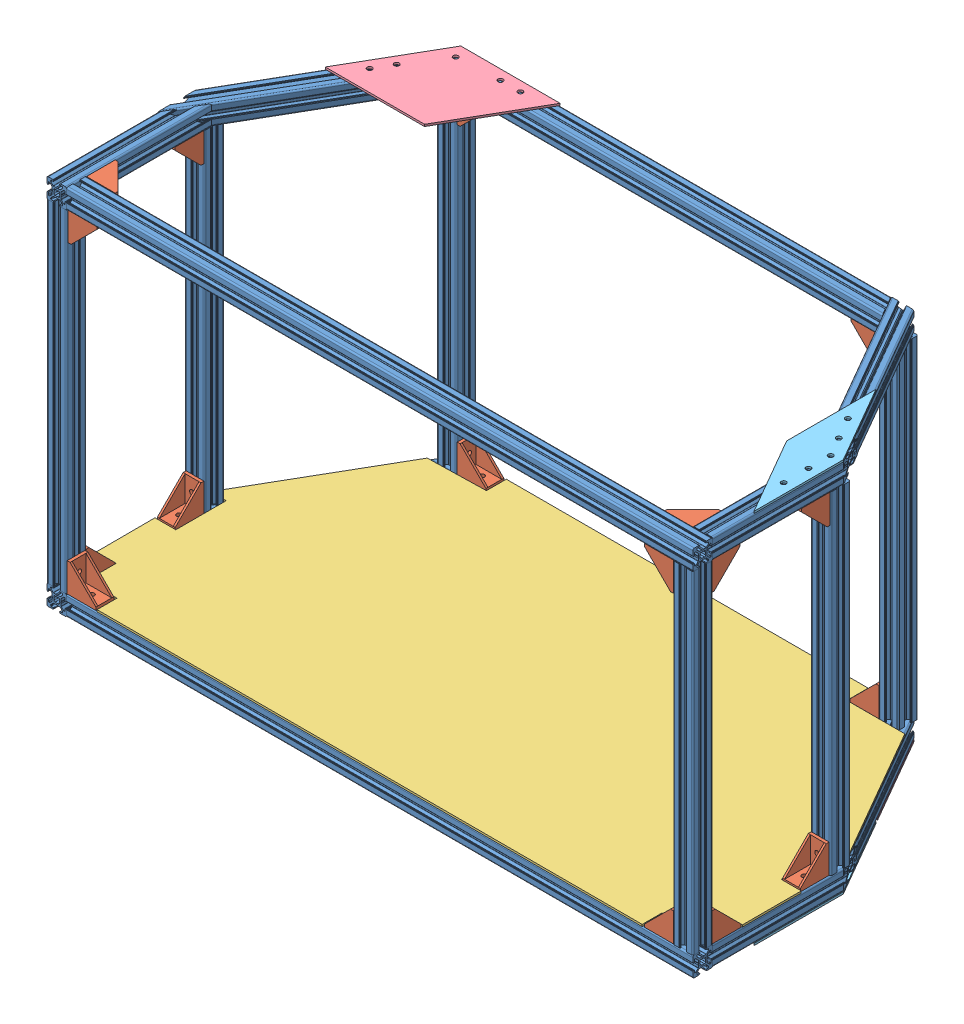
SolidWorks assembly RC, configuration Default. Lengths in mm.
Overall size (773.94 377 335.26).
30 component instances, 5 part files, 86 mates.
Components (placement in the parent):
- Rear Compartment Chassis-1: Rear Compartment Chassis [Default<As Machined>] at (565.8502 119.352 674.9495) x (0 -1 0) z (-1 0 0) size (375 320 651)
- L- Bracket-1: L- Bracket [Default] at (-55.1513 119.8531 664.9511) x (0 -1 0) z (0 0 1) size (18 29 29)
- L- Bracket-2: L- Bracket [Default] at (-55.1513 129.3509 675.4511) x (0 0 1) z (-1 0 0) size (18 29 29)
- L- Bracket-3: L- Bracket [Default] at (-64.65 129.3509 664.9506) size (18 29 29)
- L- Bracket-4: L- Bracket [Default] at (37.8598 464.3531 375.4493) x (0 0 1) z (0 1 0) size (18 29 29)
- L- Bracket-5: L- Bracket [Default] at (462.8389 464.3531 374.448) x (0 0 -1) z (0 1 0) size (18 29 29)
- L- Bracket-6: L- Bracket [Default] at (565.3487 129.3509 546.0484) x (-1 0 0) z (0 0 -1) size (18 29 29)
- L- Bracket-7: L- Bracket [Default] at (462.8389 129.3509 375.4493) x (0 0 1) z (0 -1 0) size (18 29 29)
- L- Bracket-8: L- Bracket [Default] at (565.3487 464.3531 664.9506) x (-1 0 0) z (0 0 1) size (18 29 29)
- L- Bracket-9: L- Bracket [Default] at (555.8517 119.8531 664.9511) x (0 -1 0) z (1 0 0) size (18 29 29)
- L- Bracket-10: L- Bracket [Default] at (555.85 129.3509 675.4511) x (0 0 1) z (0 -1 0) size (18 29 29)
- L- Bracket-12: L- Bracket [Default] at (566.35 129.3509 664.9506) size (18 29 29)
- L- Bracket-14: L- Bracket [Default] at (555.8517 473.8509 664.9511) x (0 1 0) z (0 0 1) size (18 29 29)
- L- Bracket-15: L- Bracket [Default] at (-55.1513 464.3531 674.4484) x (0 0 1) z (0 1 0) size (18 29 29)
- L- Bracket-17: L- Bracket [Default] at (-55.1513 474.8531 664.9511) x (0 -1 0) z (0 0 1) size (18 29 29)
- L- Bracket-19: L- Bracket [Default] at (555.85 464.3531 675.4506) x (0 0 -1) z (0 1 0) size (18 29 29)
- L- Bracket-20: L- Bracket [Default] at (566.35 464.3531 546.0484) x (-1 0 0) z (0 1 0) size (18 29 29)
- L- Bracket-21: L- Bracket [Default] at (-65.6513 464.3531 664.9506) x (1 0 0) z (0 1 0) size (18 29 29)
- L- Bracket-22: L- Bracket [Default] at (37.8598 129.3509 375.4506) x (0 0 -1) z (0 -1 0) size (18 29 29)
- L- Bracket-23: L- Bracket [Default] at (-64.65 129.3509 546.0484) x (-1 0 0) z (0 0 -1) size (18 29 29)
- L- Bracket-24: L- Bracket [Default] at (-64.65 464.3531 546.0484) x (-1 0 0) z (0 1 0) size (18 29 29)
- RC bed-1: RC bed [Default] at (-64.6253 129.3509 665.0635) x (1 0 0) z (0 1 0) size (651.19 320.03 2)
- RC shear trapzium-1: RC shear trapzium [Default] at (-27.9123 484.3509 451.5518) x (0.988224 0 -0.153016) z (0 1 0) size (161.49 93.23 2) (hidden)
- RC shear plate-5: RC shear plate [Default] at (575.8504 484.3509 623.37) x (0.258819 0 -0.965926) z (0 1 0) size (150.57 86.93 2) (hidden)
- RC shear plate-6: RC shear plate [Default] at (-30.15 484.3509 455.4277) x (-0.707107 0 0.707107) z (0 1 0) size (150.57 86.93 2) (hidden)
- RC shear plate-7: RC shear plate [Default] at (-30.15 107.3531 455.4277) x (-0.707107 0 0.707107) z (0 1 0) size (150.57 86.93 2)
- RC shear plate-8: RC shear plate [Default] at (530.8504 109.3531 455.4277) x (0.707107 0 0.707107) z (0 -1 0) size (150.57 86.93 2)
- RC shear trapzium-3: RC shear trapzium [Default] at (378.6127 484.3509 364.9493) x (0.626628 0 0.779319) z (0 1 0) size (161.49 93.23 2) (hidden)
- RC shear trapzium-4: RC shear trapzium [Default] at (528.6127 109.3531 451.5518) x (-0.988224 0 -0.153016) z (0 -1 0) size (161.49 93.23 2)
- RC shear trapzium-5: RC shear trapzium [Default] at (-27.9123 107.3531 451.5518) x (0.988224 0 -0.153016) z (0 1 0) size (161.49 93.23 2)
Mates (geometry in assembly coordinates):
- Coincident9: coincident: plane of assembly; plane of assembly; plane of Rear Compartment Chassis-1 through (-55.1513 474.352 683.4484) normal (1 0 0); plane of L- Bracket-2 through (-55.1513 158.3509 666.4511) normal (-1 0 0)
- Coincident10: coincident: line of assembly; line of assembly; line of Rear Compartment Chassis-1 through (575.8504 129.3509 666.4511) axis (-1 0 0); line of L- Bracket-2 through (-55.1513 129.3509 666.4511) axis (1 0 0)
- Coincident11: coincident: plane of assembly; plane of assembly; plane of Rear Compartment Chassis-1 through (565.8502 129.3509 678.6984) normal (0 1 0); plane of L- Bracket-2 through (-55.1513 129.3509 666.4511) normal (0 -1 0)
- Coincident12: coincident: plane of assembly; plane of assembly; plane of Rear Compartment Chassis-1 through (565.8502 123.101 664.9511) normal (0 0 -1); plane of L- Bracket-1 through (-26.1513 128.8531 664.9511) normal (0 0 1)
- Coincident13: coincident: plane of assembly; plane of assembly; plane of Rear Compartment Chassis-1 through (-55.1513 110.8531 674.9495) normal (1 0 0); plane of L- Bracket-1 through (-55.1513 128.8531 664.9511) normal (-1 0 0)
- Coincident14: coincident: line of assembly; line of assembly; line of Rear Compartment Chassis-1 through (-55.1513 110.8531 684.9497) axis (0 0 -1); line of L- Bracket-1 through (-55.1513 110.8531 664.9511) axis (0 0 -1)
- Coincident15: coincident: plane of assembly; plane of assembly; plane of Rear Compartment Chassis-1 through (555.8517 110.8531 536.0495) normal (-1 0 0); plane of L- Bracket-9 through (555.8517 128.8531 635.9511) normal (1 0 0)
- Coincident16: coincident: plane of assembly; plane of assembly; plane of Rear Compartment Chassis-1 through (565.8502 110.8531 664.9511) normal (0 0 -1); plane of L- Bracket-9 through (555.8517 128.8531 664.9511) normal (0 0 1)
- Coincident17: coincident: line of assembly; line of assembly; line of Rear Compartment Chassis-1 through (575.8504 110.8531 664.9511) axis (-1 0 0); line of L- Bracket-9 through (555.8517 110.8531 664.9511) axis (-1 0 0)
- Coincident18: coincident: plane of assembly; plane of assembly; plane of Rear Compartment Chassis-1 through (555.85 474.352 678.6984) normal (-1 0 0); plane of L- Bracket-10 through (555.85 129.3509 666.4511) normal (1 0 0)
- Coincident19: coincident: plane of assembly; plane of assembly; plane of Rear Compartment Chassis-1 through (565.8502 129.3509 678.6984) normal (0 1 0); plane of L- Bracket-10 through (526.85 129.3509 666.4511) normal (0 -1 0)
- Coincident21: coincident: line of assembly; line of assembly; line of Rear Compartment Chassis-1 through (575.8504 129.3509 666.4511) axis (-1 0 0); line of L- Bracket-10 through (526.85 129.3509 666.4511) axis (1 0 0)
- Coincident25: coincident: plane of assembly; plane of assembly; plane of Rear Compartment Chassis-1 through (557.3517 129.3509 536.0495) normal (0 1 0); plane of L- Bracket-12 through (557.35 129.3509 664.9506) normal (0 -1 0)
- Coincident26: coincident: plane of assembly; plane of assembly; plane of Rear Compartment Chassis-1 through (574.3487 474.352 664.9506) normal (0 0 -1); plane of L- Bracket-12 through (557.35 158.3509 664.9506) normal (0 0 1)
- Coincident27: coincident: line of assembly; line of assembly; line of Rear Compartment Chassis-1 through (557.35 464.3531 664.9506) axis (0 -1 0); line of L- Bracket-12 through (557.35 158.3509 664.9506) axis (0 -1 0)
- Coincident28: coincident: plane of assembly; plane of assembly; plane of Rear Compartment Chassis-1 through (562.1013 464.3531 536.0495) normal (0 -1 0); plane of L- Bracket-8 through (574.3487 464.3531 664.9506) normal (0 1 0)
- Coincident29: coincident: plane of assembly; plane of assembly; plane of Rear Compartment Chassis-1 through (562.1013 474.352 664.9506) normal (0 0 -1); plane of L- Bracket-8 through (574.3487 435.3531 664.9506) normal (0 0 1)
- Coincident30: coincident: line of assembly; line of assembly; line of Rear Compartment Chassis-1 through (574.3487 464.3531 664.9506) axis (0 -1 0); line of L- Bracket-8 through (574.3487 435.3531 664.9506) axis (0 1 0)
- Coincident31: coincident: plane of assembly; plane of assembly; plane of Rear Compartment Chassis-1 through (462.8389 474.352 378.6984) normal (-1 0 0); plane of L- Bracket-5 through (462.8389 464.3531 383.448) normal (1 0 0)
- Coincident32: coincident: plane of assembly; plane of assembly; plane of Rear Compartment Chassis-1 through (27.8613 464.3531 378.6984) normal (0 -1 0); plane of L- Bracket-5 through (433.8389 464.3531 383.448) normal (0 1 0)
- Coincident33: coincident: line of assembly; line of assembly; line of Rear Compartment Chassis-1 through (11.4075 464.3531 383.448) axis (1 0 0); line of L- Bracket-5 through (433.8389 464.3531 383.448) axis (1 0 0)
- Coincident34: coincident: plane of assembly; plane of assembly; plane of Rear Compartment Chassis-1 through (27.8613 464.3531 378.6984) normal (0 -1 0); plane of L- Bracket-4 through (66.8598 464.3531 366.4493) normal (0 1 0)
- Coincident35: coincident: plane of assembly; plane of assembly; plane of Rear Compartment Chassis-1 through (37.8598 474.352 383.4484) normal (1 0 0); plane of L- Bracket-4 through (37.8598 464.3531 366.4493) normal (-1 0 0)
- Coincident36: coincident: line of assembly; line of assembly; line of Rear Compartment Chassis-1 through (21.2217 464.3531 366.4493) axis (1 0 0); line of L- Bracket-4 through (66.8598 464.3531 366.4493) axis (-1 0 0)
- Coincident37: coincident: plane of assembly; plane of assembly; plane of Rear Compartment Chassis-1 through (462.8389 474.352 366.4506) normal (-1 0 0); plane of L- Bracket-7 through (462.8389 129.3509 366.4493) normal (1 0 0)
- Coincident38: coincident: plane of assembly; plane of assembly; plane of Rear Compartment Chassis-1 through (27.8613 129.3509 383.448) normal (0 1 0); plane of L- Bracket-7 through (433.8389 129.3509 366.4493) normal (0 -1 0)
- Coincident39: coincident: line of assembly; line of assembly; line of Rear Compartment Chassis-1 through (21.2217 129.3509 366.4493) axis (1 0 0); line of L- Bracket-7 through (433.8389 129.3509 366.4493) axis (1 0 0)
- Coincident40: coincident: plane of assembly; plane of assembly; plane of Rear Compartment Chassis-1 through (569.5991 474.352 546.0484) normal (0 0 1); plane of L- Bracket-6 through (574.3487 158.3509 546.0484) normal (0 0 -1)
- Coincident41: coincident: plane of assembly; plane of assembly; plane of Rear Compartment Chassis-1 through (557.3517 129.3509 536.0495) normal (0 1 0); plane of L- Bracket-6 through (574.3487 129.3509 546.0484) normal (0 -1 0)
- Coincident42: coincident: line of assembly; line of assembly; line of Rear Compartment Chassis-1 through (574.3487 464.3531 546.0484) axis (0 -1 0); line of L- Bracket-6 through (574.3487 158.3509 546.0484) axis (0 -1 0)
- Coincident43: coincident: plane of assembly; plane of assembly; plane of Rear Compartment Chassis-1 through (555.8517 465.8531 536.0495) normal (-1 0 0); plane of L- Bracket-14 through (555.8517 464.8509 664.9511) normal (1 0 0)
- Coincident44: coincident: line of assembly; line of assembly; line of Rear Compartment Chassis-1 through (575.8504 482.8509 664.9511) axis (-1 0 0); line of L- Bracket-14 through (526.8517 482.8509 664.9511) axis (1 0 0)
- Coincident45: coincident: plane of assembly; plane of assembly; plane of Rear Compartment Chassis-1 through (565.8502 465.8531 664.9511) normal (0 0 -1); plane of L- Bracket-14 through (526.8517 464.8509 664.9511) normal (0 0 1)
- Coincident52: coincident: plane of assembly; plane of assembly; plane of Rear Compartment Chassis-1 through (555.85 474.352 678.6984) normal (-1 0 0); plane of L- Bracket-19 through (555.85 464.3531 684.4506) normal (1 0 0)
- Coincident53: coincident: plane of assembly; plane of assembly; plane of Rear Compartment Chassis-1 through (565.8502 464.3531 671.2006) normal (0 -1 0); plane of L- Bracket-19 through (526.85 464.3531 684.4506) normal (0 1 0)
- Coincident54: coincident: line of assembly; line of assembly; line of Rear Compartment Chassis-1 through (555.85 464.3531 666.4506) axis (0 -1 0); line of L- Bracket-19 through (555.85 464.3531 666.4506) axis (0 -1 0)
- Coincident57: coincident: plane of assembly; plane of assembly; plane of Rear Compartment Chassis-1 through (557.35 474.352 546.0484) normal (0 0 1); plane of L- Bracket-20 through (575.35 464.3531 546.0484) normal (0 0 -1)
- Coincident58: coincident: plane of assembly; plane of assembly; plane of Rear Compartment Chassis-1 through (562.1013 464.3531 536.0495) normal (0 -1 0); plane of L- Bracket-20 through (575.35 464.3531 575.0484) normal (0 1 0)
- Coincident59: coincident: cylinder of assembly; line of assembly; cylinder of Rear Compartment Chassis-1 through (557.35 474.352 544.5484) axis (0 -1 0) radius 1.5; line of L- Bracket-20 through (557.35 464.3531 546.0484) axis (0 -1 0)
- Coincident60: coincident: plane of assembly; plane of assembly; plane of Rear Compartment Chassis-1 through (-55.1513 474.352 671.2006) normal (1 0 0); plane of L- Bracket-15 through (-55.1513 464.3531 665.4484) normal (-1 0 0)
- Coincident61: coincident: plane of assembly; plane of assembly; plane of Rear Compartment Chassis-1 through (565.8502 464.3531 671.2006) normal (0 -1 0); plane of L- Bracket-15 through (-26.1513 464.3531 665.4484) normal (0 1 0)
- Coincident62: coincident: line of assembly; line of assembly; line of Rear Compartment Chassis-1 through (-55.1513 464.3531 683.4484) axis (0 -1 0); line of L- Bracket-15 through (-55.1513 464.3531 683.4484) axis (0 -1 0)
- Coincident63: coincident: plane of assembly; plane of assembly; plane of Rear Compartment Chassis-1 through (-55.1513 465.8531 674.9495) normal (1 0 0); plane of L- Bracket-17 through (-55.1513 483.8531 664.9511) normal (-1 0 0)
- Coincident64: coincident: plane of assembly; plane of assembly; plane of Rear Compartment Chassis-1 through (565.8502 465.8531 664.9511) normal (0 0 -1); plane of L- Bracket-17 through (-26.1513 483.8531 664.9511) normal (0 0 1)
- Coincident65: coincident: line of assembly; line of assembly; line of Rear Compartment Chassis-1 through (575.8504 465.8531 664.9511) axis (-1 0 0); line of L- Bracket-17 through (-26.1513 465.8531 664.9511) axis (-1 0 0)
- Coincident66: coincident: plane of assembly; plane of assembly; plane of Rear Compartment Chassis-1 through (-68.8987 474.352 664.9506) normal (0 0 -1); plane of L- Bracket-21 through (-74.6513 464.3531 664.9506) normal (0 0 1)
- Coincident67: coincident: plane of assembly; plane of assembly; plane of Rear Compartment Chassis-1 through (-73.65 464.3531 674.9495) normal (0 -1 0); plane of L- Bracket-21 through (-74.6513 464.3531 635.9506) normal (0 1 0)
- Coincident68: coincident: line of assembly; line of assembly; line of Rear Compartment Chassis-1 through (-56.6513 464.3531 684.9497) axis (0 0 -1); line of L- Bracket-21 through (-56.6513 464.3531 635.9506) axis (0 0 1)
- Coincident69: coincident: plane of assembly; plane of assembly; plane of Rear Compartment Chassis-1 through (27.8613 129.3509 383.448) normal (0 1 0); plane of L- Bracket-22 through (66.8598 129.3509 384.4506) normal (0 -1 0)
- Coincident70: coincident: plane of assembly; plane of assembly; plane of Rear Compartment Chassis-1 through (37.8598 474.352 383.4484) normal (1 0 0); plane of L- Bracket-22 through (37.8598 129.3509 384.4506) normal (-1 0 0)
- Coincident71: coincident: line of assembly; line of assembly; line of Rear Compartment Chassis-1 through (37.8598 464.3531 366.4506) axis (0 -1 0); line of L- Bracket-22 through (37.8598 129.3509 366.4506) axis (0 1 0)
- Coincident72: coincident: plane of assembly; plane of assembly; plane of Rear Compartment Chassis-1 through (-73.65 474.352 546.0484) normal (0 0 1); plane of L- Bracket-23 through (-55.65 158.3509 546.0484) normal (0 0 -1)
- Coincident73: coincident: plane of assembly; plane of assembly; plane of Rear Compartment Chassis-1 through (-68.8987 129.3509 674.9495) normal (0 1 0); plane of L- Bracket-23 through (-55.65 129.3509 546.0484) normal (0 -1 0)
- Coincident74: coincident: line of assembly; line of assembly; line of Rear Compartment Chassis-1 through (-73.65 129.3509 684.9497) axis (0 0 -1); line of L- Bracket-23 through (-73.65 129.3509 546.0484) axis (0 0 1)
- Coincident75: coincident: plane of assembly; plane of assembly; plane of Rear Compartment Chassis-1 through (-73.65 464.3531 674.9495) normal (0 -1 0); plane of L- Bracket-24 through (-55.65 464.3531 575.0484) normal (0 1 0)
- Coincident76: coincident: plane of assembly; plane of assembly; plane of Rear Compartment Chassis-1 through (-73.65 474.352 546.0484) normal (0 0 1); plane of L- Bracket-24 through (-55.65 464.3531 546.0484) normal (0 0 -1)
- Coincident77: coincident: line of assembly; line of assembly; line of Rear Compartment Chassis-1 through (-73.65 464.3531 546.0484) axis (0 -1 0); line of L- Bracket-24 through (-73.65 464.3531 546.0484) axis (0 -1 0)
- Coincident78: coincident: plane of assembly; plane of assembly; plane of Rear Compartment Chassis-1 through (-68.8987 129.3509 674.9495) normal (0 1 0); plane of L- Bracket-3 through (-73.65 129.3509 664.9506) normal (0 -1 0)
- Coincident79: coincident: plane of assembly; plane of assembly; plane of Rear Compartment Chassis-1 through (-68.8987 474.352 664.9506) normal (0 0 -1); plane of L- Bracket-3 through (-73.65 158.3509 664.9506) normal (0 0 1)
- Coincident80: coincident: line of assembly; line of assembly; line of Rear Compartment Chassis-1 through (-73.65 129.3509 684.9497) axis (0 0 -1); line of L- Bracket-3 through (-73.65 129.3509 664.9506) axis (0 0 -1)
- Coincident81: coincident: plane of assembly; plane of assembly; plane of Rear Compartment Chassis-1 through (27.8613 129.3509 383.448) normal (0 1 0); plane of RC bed-1 through (-64.6253 129.3509 665.0635) normal (0 -1 0)
- Lock1: lock: unknown of Rear Compartment Chassis-1; unknown of RC bed-1
- Coincident100: coincident: plane of assembly; plane of assembly; plane of Rear Compartment Chassis-1 through (465.4792 484.3509 379.1988) normal (0 1 0); plane of RC shear plate-5 through (575.8504 484.3509 623.37) normal (0 -1 0)
- Coincident101: coincident: plane of assembly; plane of assembly; plane of Rear Compartment Chassis-1 through (481.4995 482.8509 369.9494) normal (0.866025 0 -0.5); plane of RC shear plate-5 through (575.8504 486.3509 533.37) normal (0.866025 0 -0.5)
- Coincident102: coincident: plane of assembly; plane of assembly; plane of Rear Compartment Chassis-1 through (575.8504 482.8509 536.0495) normal (1 0 0); plane of RC shear plate-5 through (575.8504 486.3509 623.37) normal (1 0 0)
- Coincident103: coincident: plane of assembly; plane of assembly; plane of Rear Compartment Chassis-1 through (-61.4009 109.3531 674.9495) normal (0 -1 0); plane of RC shear plate-7 through (-30.15 109.3531 455.4277) normal (0 1 0)
- Coincident104: coincident: plane of assembly; plane of assembly; plane of Rear Compartment Chassis-1 through (-75.15 115.6031 674.9495) normal (-1 0 0); plane of RC shear plate-7 through (-75.15 109.3531 533.37) normal (-1 0 0)
- Coincident105: coincident: plane of assembly; plane of assembly; plane of Rear Compartment Chassis-1 through (-73.8102 115.6031 531.0494) normal (-0.866025 0 -0.5); plane of RC shear plate-7 through (-30.15 109.3531 455.4277) normal (-0.866025 0 -0.5)
- Coincident106: coincident: plane of assembly; plane of assembly; plane of Rear Compartment Chassis-1 through (574.3504 109.3531 536.0495) normal (0 -1 0); plane of RC shear plate-8 through (530.8504 109.3531 455.4277) normal (0 1 0)
- Coincident107: coincident: plane of assembly; plane of assembly; plane of Rear Compartment Chassis-1 through (575.8504 115.6031 536.0495) normal (1 0 0); plane of RC shear plate-8 through (575.8504 107.3531 533.37) normal (1 0 0)
- Coincident108: coincident: plane of assembly; plane of assembly; plane of Rear Compartment Chassis-1 through (481.4995 115.6031 369.9494) normal (0.866025 0 -0.5); plane of RC shear plate-8 through (530.8504 107.3531 455.4277) normal (0.866025 0 -0.5)
- Coincident109: coincident: plane of assembly; plane of assembly; plane of Rear Compartment Chassis-1 through (-68.3965 484.3509 534.1751) normal (0 1 0); plane of RC shear plate-6 through (-30.15 484.3509 455.4277) normal (0 -1 0)
- Coincident111: coincident: plane of assembly; plane of assembly; plane of Rear Compartment Chassis-1 through (-73.8102 482.8509 531.0494) normal (-0.866025 0 -0.5); plane of RC shear plate-6 through (-30.15 486.3509 455.4277) normal (-0.866025 0 -0.5)
- Coincident112: coincident: plane of assembly; plane of assembly; plane of Rear Compartment Chassis-1 through (-75.15 482.8509 674.9495) normal (-1 0 0); plane of RC shear plate-6 through (-75.15 486.3509 533.37) normal (-1 0 0)
- Coincident113: coincident: plane of assembly; plane of assembly; plane of Rear Compartment Chassis-1 through (476.0857 484.3509 373.0751) normal (0 1 0); plane of RC shear trapzium-3 through (378.6127 484.3509 364.9493) normal (0 -1 0)
- Coincident114: coincident: plane of assembly; plane of assembly; plane of Rear Compartment Chassis-1 through (481.4995 482.8509 369.9494) normal (0.866025 0 -0.5); plane of RC shear trapzium-3 through (478.6127 486.3509 364.9493) normal (0.866025 0 -0.5)
- Coincident115: coincident: plane of assembly; plane of assembly; plane of Rear Compartment Chassis-1 through (27.8613 482.8509 364.9493) normal (0 0 -1); plane of RC shear trapzium-3 through (378.6127 486.3509 364.9493) normal (0 0 -1)
- Coincident116: coincident: plane of assembly; plane of assembly; plane of Rear Compartment Chassis-1 through (27.8613 109.3531 366.4493) normal (0 -1 0); plane of RC shear trapzium-4 through (528.6127 109.3531 451.5518) normal (0 1 0)
- Coincident117: coincident: plane of assembly; plane of assembly; plane of Rear Compartment Chassis-1 through (27.8613 115.6031 364.9493) normal (0 0 -1); plane of RC shear trapzium-4 through (478.6127 107.3531 364.9493) normal (0 0 -1)
- Coincident118: coincident: plane of assembly; plane of assembly; plane of Rear Compartment Chassis-1 through (481.4995 115.6031 369.9494) normal (0.866025 0 -0.5); plane of RC shear trapzium-4 through (528.6127 107.3531 451.5518) normal (0.866025 0 -0.5)
- Coincident119: coincident: plane of assembly; plane of assembly; plane of Rear Compartment Chassis-1 through (-61.9031 109.3531 537.924) normal (0 -1 0); plane of RC shear trapzium-5 through (-27.9123 109.3531 451.5518) normal (0 1 0)
- Coincident120: coincident: plane of assembly; plane of assembly; plane of Rear Compartment Chassis-1 through (-73.8102 115.6031 531.0494) normal (-0.866025 0 -0.5); plane of RC shear trapzium-5 through (-27.9123 109.3531 451.5518) normal (-0.866025 0 -0.5)
- Coincident121: coincident: plane of assembly; plane of assembly; plane of Rear Compartment Chassis-1 through (27.8613 127.8509 364.9493) normal (0 0 -1); plane of RC shear trapzium-5 through (22.0877 109.3531 364.9493) normal (0 0 -1)
- Coincident124: coincident: plane of assembly; plane of assembly; plane of Rear Compartment Chassis-1 through (27.8613 484.3509 383.448) normal (0 1 0); plane of RC shear trapzium-1 through (-27.9123 484.3509 451.5518) normal (0 -1 0)
- Coincident126: coincident: plane of assembly; plane of assembly; plane of Rear Compartment Chassis-1 through (-73.8102 482.8509 531.0494) normal (-0.866025 0 -0.5); plane of RC shear trapzium-1 through (-27.9123 486.3509 451.5518) normal (-0.866025 0 -0.5)
- Coincident127: coincident: plane of assembly; plane of assembly; plane of Rear Compartment Chassis-1 through (27.8613 482.8509 364.9493) normal (0 0 -1); plane of RC shear trapzium-1 through (22.0877 486.3509 364.9493) normal (0 0 -1)
